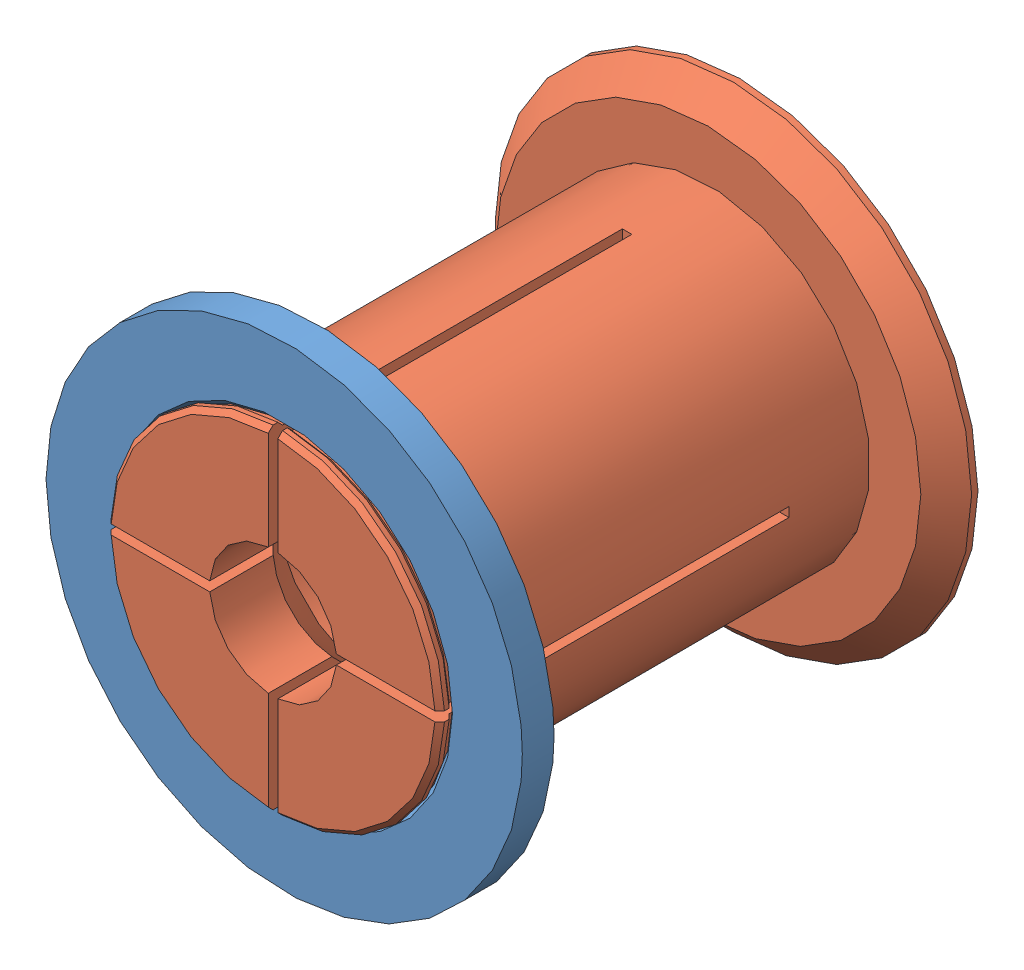
SolidWorks assembly Assem1, configuration Default. Lengths in mm.
Overall size (75 75 73.5).
2 component instances, 2 part files, 1 mates.
Components (placement in the parent):
- 52-62-20-spool-adapter-female-1: 52-62-20-spool-adapter-female [Default] at (5.8661 42.6485 64.362) size (75 75 5)
- 52-62-20-spool-adapter-male-1: 52-62-20-spool-adapter-male [Default] at (5.8661 42.6485 2.612) size (75 75 73.5)
Mates (geometry in assembly coordinates):
- Coincident1: coincident aligned: cone of 52-62-20-spool-adapter-female-1 through (5.8661 42.6485 65.112) axis (0 0 1); cone of 52-62-20-spool-adapter-male-1 through (5.8661 42.6485 65.362) axis (0 0 1)
